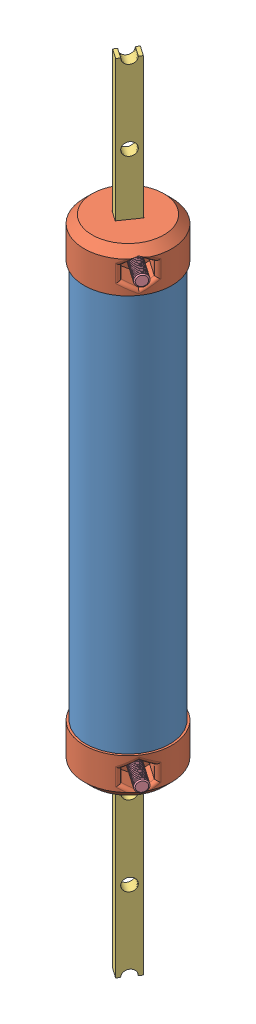
SolidWorks assembly Assem1, configuration Default. Lengths in mm.
Overall size (31.1 200 30.96).
6 component instances, 4 part files, 12 mates.
Components (placement in the parent):
- Part2-1: Part2 [Default] at (-8.9642 4.4733 133.6009) size (21 100 21)
- Part3-1: Part3 [Default] at (-8.9642 -5.5267 133.6009) x (0.821008 0 0.570916) z (-0.570916 0 0.821008) size (22.59 20 22)
- Part3-2: Part3 [Default] at (-8.9642 114.4733 133.6009) x (0.821008 0 0.570916) z (0.570916 0 -0.821008) size (22.59 20 22)
- Part5-2: Part5 [200mm] at (-11.623 -50.2826 134.7971) x (0 1 0) z (0.570916 0 -0.821008) size (200 3 5)
- pan head cross recess screw_iso-1: pan head cross recess screw_iso [ISO 7045 - M3 x 20 - Z - 20S] at (-15.8607 109.7174 128.8052) x (0.821008 0 0.570916) z (-0.162018 -0.958887 0.232991) size (22.35 5.6 5.6)
- pan head cross recess screw_iso-2: pan head cross recess screw_iso [ISO 7045 - M3 x 20 - Z - 20S] at (-15.8607 -0.2826 128.8052) x (0.821008 0 0.570916) z (-0.018252 0.999489 0.026247) size (22.35 5.6 5.6)
Mates (geometry in assembly coordinates):
- Concentric1: concentric aligned: cylinder of Part2-1 through (-8.9642 104.4733 133.6009) axis (0 -1 0) radius 9.5; cylinder of Part3-1 through (-8.9642 14.4733 133.6009) axis (0 -1 0) radius 9.3
- Coincident1: coincident anti-aligned: plane of Part2-1 through (-8.9642 4.4733 133.6009) normal (0 -1 0); plane of Part3-1 through (-8.9642 4.4733 133.6009) normal (0 1 0)
- Concentric2: concentric anti-aligned: cylinder of Part2-1 through (-8.9642 104.4733 133.6009) axis (0 -1 0) radius 9.5; cylinder of Part3-2 through (-8.9642 94.4733 133.6009) axis (0 1 0) radius 9.3
- Coincident2: coincident anti-aligned: plane of Part2-1 through (-8.9642 104.4733 133.6009) normal (0 1 0); plane of Part3-2 through (-8.9642 104.4733 133.6009) normal (0 -1 0)
- Distance2: distance = 0.1 mm anti-aligned: plane of Part5-2 through (-9.16 -50.2826 136.5098) normal (0.821008 0 0.570916); plane of Part3-2 through (-6.1662 94.4733 132.3798) normal (-0.821008 0 -0.570916)
- Distance3: distance = 0.1 mm anti-aligned: plane of Part5-2 through (-6.3054 -50.2826 132.4048) normal (0.570916 0 -0.821008); plane of Part3-2 through (-8.7934 94.4733 130.5529) normal (-0.570916 0 0.821008)
- Coincident13: coincident aligned: plane of Part3-1 through (-4.8592 -5.5267 136.4555) normal (0.821008 0 0.570916); plane of Part3-2 through (-4.8592 114.4733 136.4555) normal (0.821008 0 0.570916)
- Concentric13: concentric anti-aligned: cylinder of Part3-1 through (-17.9953 -0.2826 127.3209) axis (0.821008 0 0.570916) radius 1.6; cylinder of pan head cross recess screw_iso-2 through (-36.7143 -0.2826 114.304) axis (-0.821008 0 -0.570916) radius 1.5
- Concentric16: concentric anti-aligned: cylinder of Part5-2 through (-10.1957 109.7174 132.7446) axis (0.821008 0 0.570916) radius 1.6; cylinder of pan head cross recess screw_iso-1 through (-36.7143 109.7174 114.304) axis (-0.821008 0 -0.570916) radius 1.5
- Coincident14: coincident aligned: plane of pan head cross recess screw_iso-1 through (-14.7114 110.1431 131.3563) normal (0.821008 0 0.570916); plane of pan head cross recess screw_iso-2 through (-13.0343 -0.2347 128.9446) normal (0.821008 0 0.570916)
- Distance4: distance = 110 mm: cylinder of pan head cross recess screw_iso-1 through (-36.7143 109.7174 114.304) axis (-0.821008 0 -0.570916) radius 2.8; cylinder of pan head cross recess screw_iso-2 through (-36.7143 -0.2826 114.304) axis (-0.821008 0 -0.570916) radius 2.8
- Distance5: distance = 1 mm anti-aligned: plane of Part3-1 through (-13.0693 -0.2826 130.7464) normal (-0.821008 0 -0.570916); plane of pan head cross recess screw_iso-2 through (-13.0343 -0.2347 128.9446) normal (0.821008 0 0.570916)
